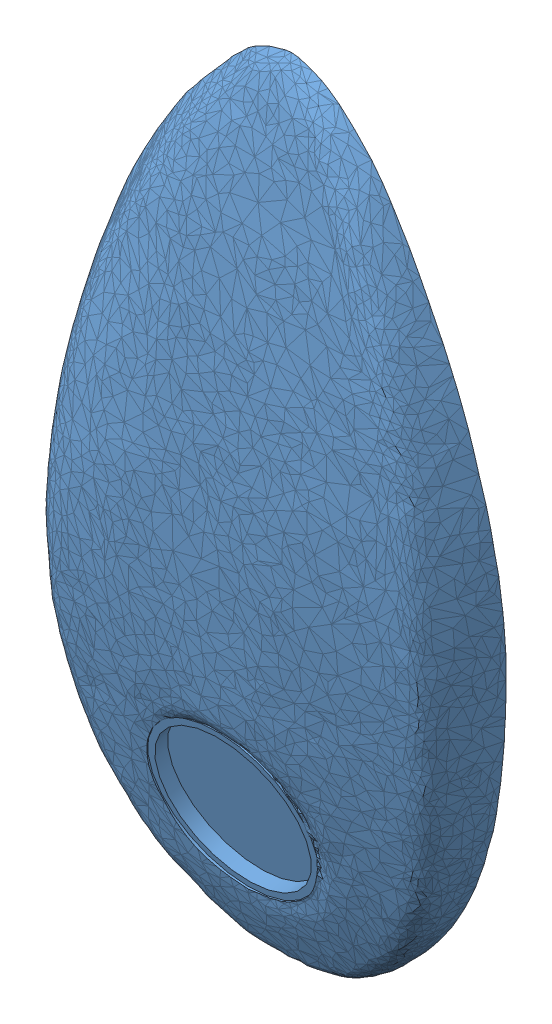
SolidWorks assembly Assem8, configuration Default. Lengths in mm.
Overall size (74.04 119.76 22.22).
2 component instances, 2 part files, 4 mates.
Components (placement in the parent):
- part_housingPrepared-1: part_housingPrepared [Default] at (1.4093 9.2175 -30.0595) size (64.09 119.76 15.04)
- housing-1: housing [Default] at (3.7767 -43.497 -7.7562) x (0.459987 0.88703 -0.039871) z (-0.876935 0.460879 0.136293) size (60.5 8.65 49)
Mates (geometry in assembly coordinates):
- Parallel2: parallel: plane of part_housingPrepared-1 through (-2.3183 -37.7088 -0.5116) normal (0.023854 -0.241496 0.970108); plane of housing-1 through (-7.3086 -45.5414 -3.2723) normal (0.023854 -0.241496 0.970108)
- Coincident4: coincident: plane of part_housingPrepared-1 through (-2.3183 -37.7088 -0.5116) normal (0.023854 -0.241496 0.970108); line of housing-1 through (-10.2141 -31.2424 1.2923) axis (-0.172195 -0.956874 -0.233968)
- Coincident5: coincident: line of part_housingPrepared-1 through (-2.2267 -38.6357 3.2117) axis (-0.023854 0.241496 -0.970108); point of housing-1
- Parallel4: parallel anti-aligned: line of part_housingPrepared-1 through (6.9394 -36.1224 3.612) axis (-0.876935 0.460879 0.136293); line of housing-1 through (-11.2116 -42.9202 -1.5902) axis (0.876935 -0.460879 -0.136293)
